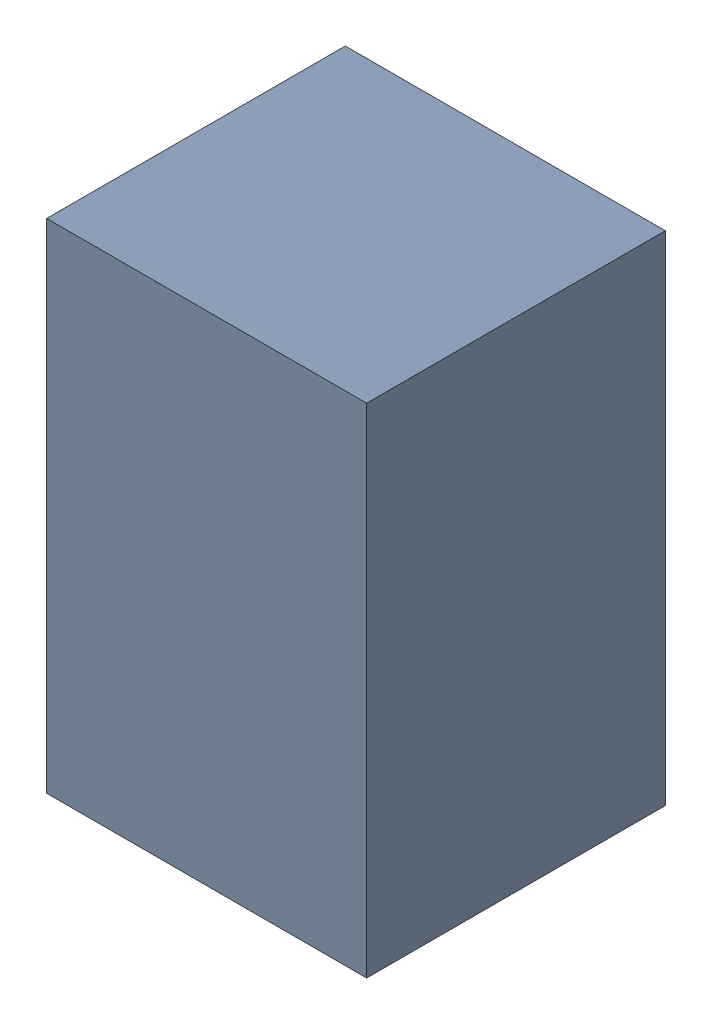
SolidWorks assembly C3_1, configuration Default. Lengths in mm.
Overall size (1.35 2.1 1.26).
2 component instances, 1 part files, 0 mates.
Components (placement in the parent):
- 407985696_1-1: 407985696_1 [Default] at (52.832 6.096 0.0127) size (1.35 2.1 1.26)
  - Extruded_6-1: Extruded_6 [Default] at origin size (1.35 2.1 1.26)
